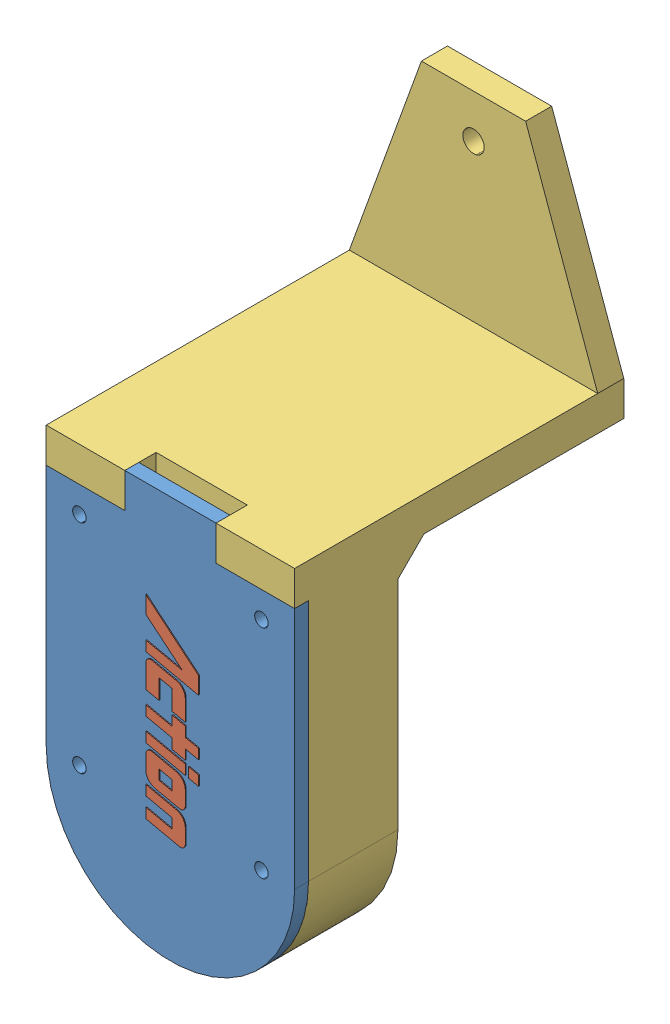
SolidWorks assembly 编码器电路板改, configuration Default. Lengths in mm.
Overall size (28.6 69.3 38).
3 component instances, 3 part files, 6 mates.
Components (placement in the parent):
- 编码器电路板改-1: 编码器电路板改 [默认] at (-41.1539 1.1601 26.4304) size (28.6 46.3 1.6)
- ACTION-1: ACTION [默认] at (-1043.6196 -1187.5043 28.0304) x (0 -1 0) z (0 0 1) size (23.21 6.06 0.1)
- 弯折改-1: 弯折改 [默认] at (-41.1539 1.1601 16.1304) size (28.6 69.3 37.9)
Mates (geometry in assembly coordinates):
- 重合1: coincident anti-aligned: plane of 编码器电路板改-1 through (-41.1539 1.1601 28.0304) normal (0 0 1); plane of ACTION-1 through (-1043.6196 -1187.5043 28.0304) normal (0 0 -1)
- 平行1: parallel aligned: plane of 编码器电路板改-1 through (-78.366 1.1601 28.0304) normal (-1 0 0); plane of ACTION-1 through (-66.8002 -1187.5043 28.1304) normal (-1 0 0)
- 锁定1: lock: unknown of 编码器电路板改-1; unknown of ACTION-1
- 同心2: concentric aligned: cylinder of 编码器电路板改-1 through (-74.546 25.8299 28.0304) axis (0 0 -1) radius 0.7835; cylinder of 弯折改-1 through (-74.546 25.8299 26.4304) axis (0 0 -1) radius 0.7835
- 同心3: concentric aligned: cylinder of 编码器电路板改-1 through (-53.586 25.8299 28.0304) axis (0 0 -1) radius 0.7835; cylinder of 弯折改-1 through (-53.586 25.8299 26.4304) axis (0 0 -1) radius 0.7835
- 重合4: coincident anti-aligned: plane of 编码器电路板改-1 through (-41.1539 1.1601 26.4304) normal (0 0 -1); plane of 弯折改-1 through (-41.1539 1.1601 26.4304) normal (0 0 1)
